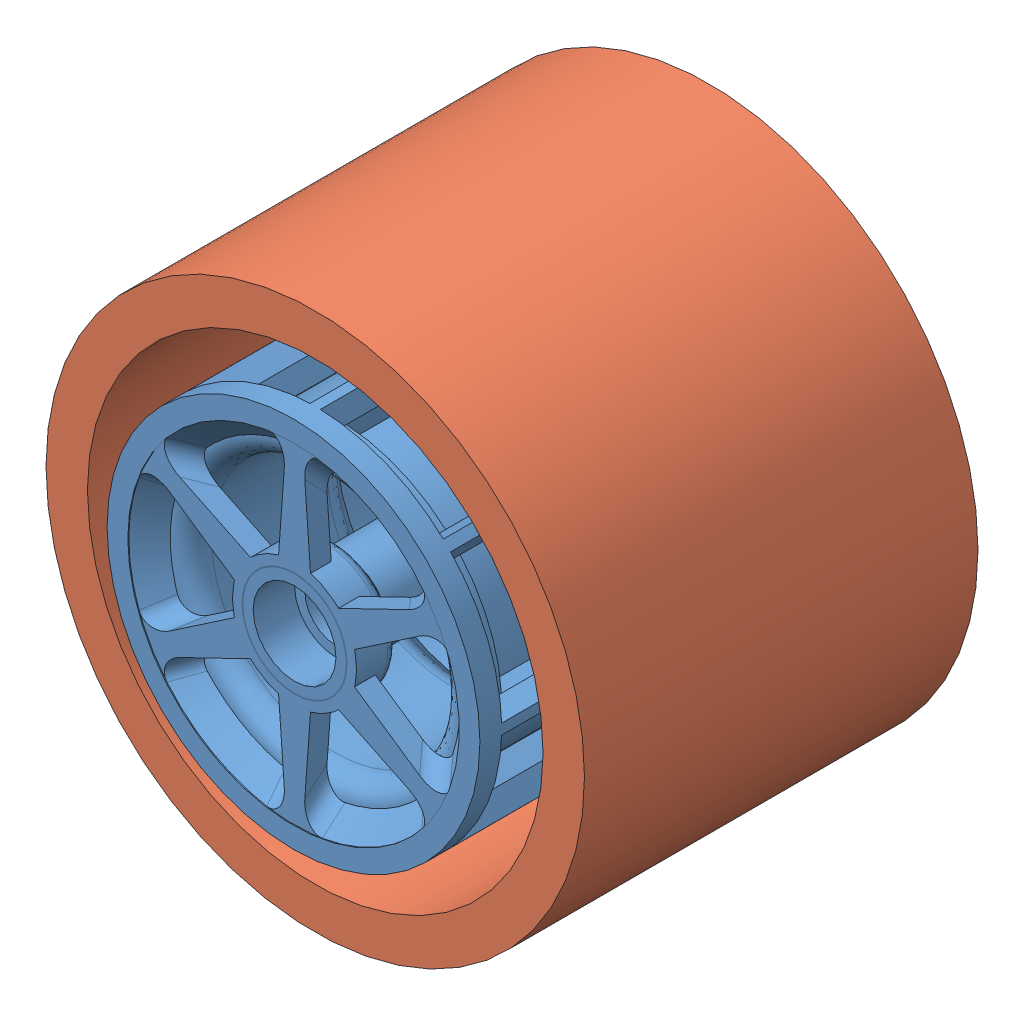
SolidWorks assembly Montagemdaroda, configuration Valor predeterminado. Lengths in mm.
Overall size (26 26 20.05).
2 component instances, 2 part files, 1 mates.
Components (placement in the parent):
- eixo-9: eixo [Valor predeterminado] at (28.9503 -44.1178 -16.5158) size (18 18 19.05)
- molde2-4: molde2 [Valor predeterminado] at (28.9503 -44.1178 -33.5158) size (26 26 19)
Mates (geometry in assembly coordinates):
- Concêntrico1: concentric anti-aligned: circle of eixo-9; circle of molde2-4
